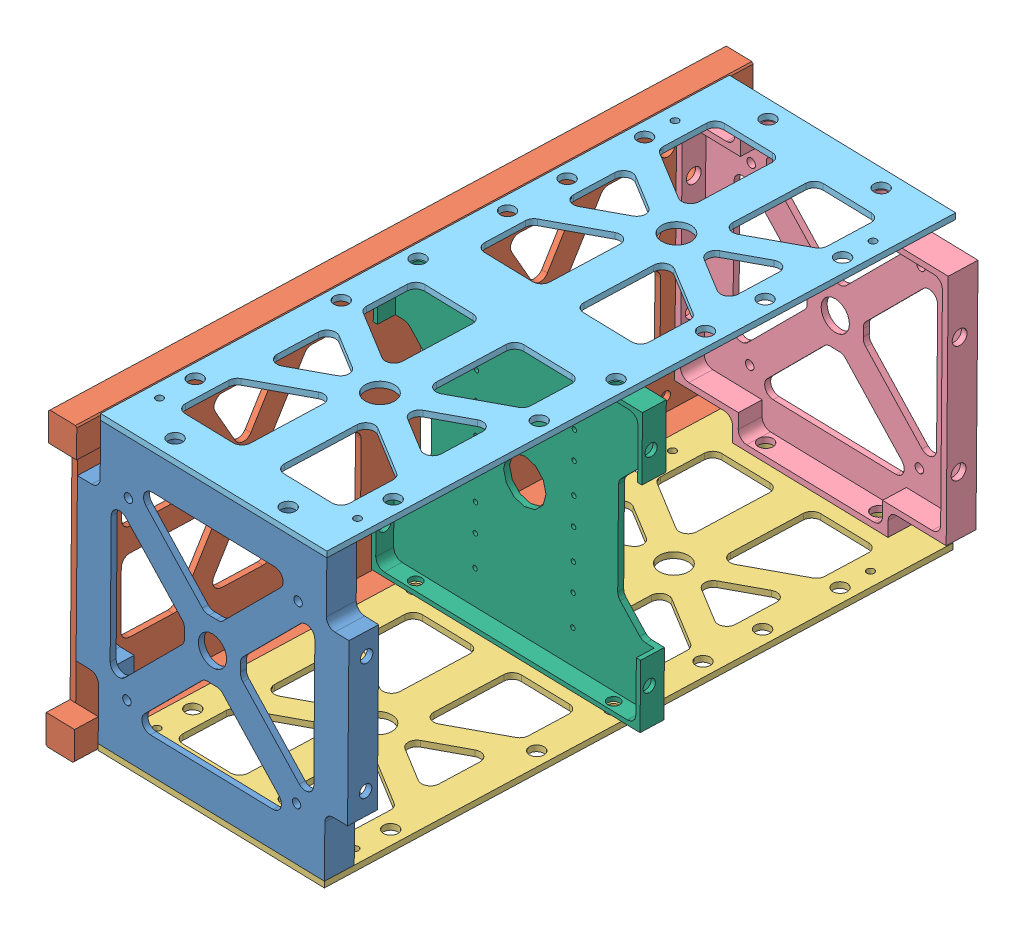
SolidWorks assembly REALOP_1_EDU, configuration Default. Lengths in mm.
Overall size (103.69 101.98 228.05).
6 component instances, 6 part files, 8 mates.
Components (placement in the parent):
- Z_FACE_1_EDU-1: Z_FACE_1_EDU [Default] at (61.9257 -10.7824 71.3689) x (-0.999658 -0.000228 -0.026138) z (0 -0.999962 0.008727) size (96 10 96)
- X_FACE_EDU-2: X_FACE_EDU [Default] at (-28.5262 79.3515 -142.8631) x (0 -0.999962 0.008727) z (-0.999658 -0.000228 -0.026138) size (100 227 10)
- Y_FACE_1_EDU-1: Y_FACE_1_EDU [Default] at (-24.5276 -12.6441 -141.9557) x (0.999658 0.000228 0.026138) z (0 -0.999962 0.008727) size (80 211 2)
- Z_FACE_2_EDU-1: Z_FACE_2_EDU [Default] at (-28.5262 83.3513 -142.898) x (0 -0.999962 0.008727) z (-0.999658 -0.000228 -0.026138) size (96 10 96)
- Y_FACE_2_EDU-1: Y_FACE_2_EDU [Default] at (-24.5276 85.3522 -142.8109) x (0.999658 0.000228 0.026138) z (0 -0.999962 0.008727) size (80 211 2)
- BATTERY_MOUNTING_BRACKET_EDU-1: BATTERY_MOUNTING_BRACKET_EDU [Default] at (16.7337 36.6657 -37.0675) x (0.999658 0.000228 0.026138) z (-0.026139 0.008724 0.99962) size (95 95 8)
Mates (geometry in assembly coordinates):
- Coincident1: coincident anti-aligned: circle of Z_FACE_1_EDU-1; circle of X_FACE_EDU-2
- Coincident3: coincident aligned: circle of Z_FACE_1_EDU-1; circle of Y_FACE_1_EDU-1
- Coincident4: coincident aligned: circle of Y_FACE_1_EDU-1; circle of Z_FACE_2_EDU-1
- Coincident5: coincident anti-aligned: circle of X_FACE_EDU-2; circle of Z_FACE_2_EDU-1
- Coincident7: coincident anti-aligned: circle of Z_FACE_1_EDU-1; circle of Y_FACE_2_EDU-1
- Coincident8: coincident anti-aligned: circle of Z_FACE_1_EDU-1; circle of Y_FACE_2_EDU-1
- Concentric1: concentric anti-aligned: circle of Y_FACE_1_EDU-1; circle of BATTERY_MOUNTING_BRACKET_EDU-1
- Concentric2: concentric anti-aligned: circle of Y_FACE_1_EDU-1; circle of BATTERY_MOUNTING_BRACKET_EDU-1
